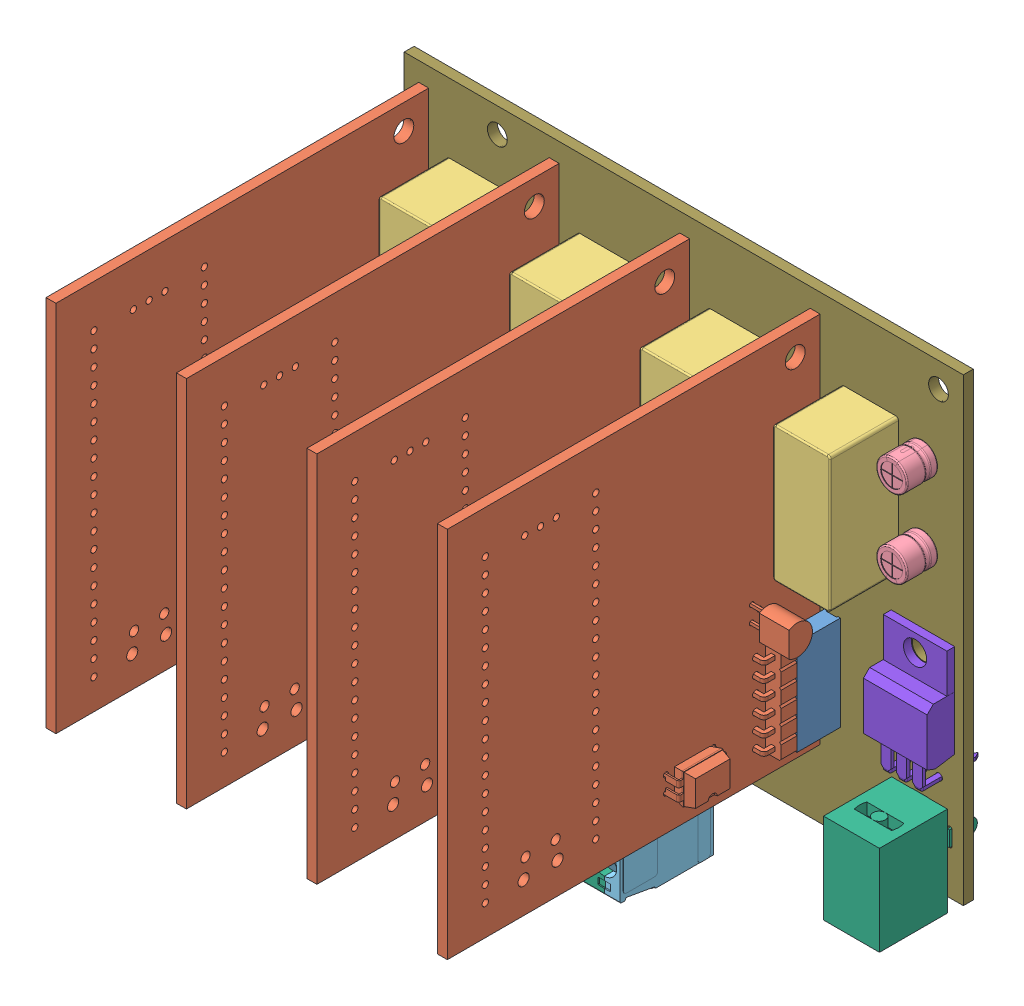
SolidWorks assembly scbs_array_pcba, configuration Default. Lengths in mm.
Overall size (91.35 87.17 67.03).
79 component instances, 27 part files, 3 mates.
Components (placement in the parent):
- PinSocket_1x06_P2.54mm_Vertical-1: PinSocket_1x06_P2.54mm_Vertical [PinSocket_1x06_P2.54mm_Vertical] at (47 -65 1.65) size (2.54 15.24 10.1)
  - SOLID-1: SOLID [SOLID] at origin size (2.54 15.24 10.1)
- scbs_pico-1: scbs_pico [scbs_pico] at (45.7 -102.3 87.35) x (0 0 -1) z (-1 0 0) size (60 60 13.4)
  - COMPOUND-1: COMPOUND [COMPOUND] at origin size (60 60 13.4)
- Converter_DCDC_TRACO_TMR-xxxx_THT-1: Converter_DCDC_TRACO_TMR-xxxx_THT [Converter_DCDC_TRACO_TMR-xxxx_THT] at (33 -33 1.65) x (0 -1 0) z (0 0 1) size (21.8 9.2 15)
  - SOLID-0-1: SOLID-0 [SOLID-0] at origin size (21.8 9.2 15)
- CP_Radial_D5.0mm_P2.50mm-1: CP_Radial_D5.0mm_P2.50mm [CP_Radial_D5.0mm_P2.50mm] at (61 -46 1.65) x (0 -1 0) z (0 0 1) size (6.13 6.52 7)
  - SOLID-1-1: SOLID-1 [SOLID-1] at origin size (6.13 6.52 7)
- CP_Radial_D5.0mm_P2.50mm-2: CP_Radial_D5.0mm_P2.50mm [CP_Radial_D5.0mm_P2.50mm] at (103.5 -46 1.65) x (0 -1 0) z (0 0 1) size (6.13 6.52 7)
  - SOLID-1-1: SOLID-1 [SOLID-1] at origin size (6.13 6.52 7)
- PinHeader_1x03_P2.54mm_Horizontal-1: PinHeader_1x03_P2.54mm_Horizontal [PinHeader_1x03_P2.54mm_Horizontal] at (36 -86 1.65) x (0 -1 0) z (0 0 1) size (10.36 7.62 5.54)
  - SOLID-2-1: SOLID-2 [SOLID-2] at origin size (10.36 7.62 5.54)
- CP_Radial_D5.0mm_P2.50mm-3: CP_Radial_D5.0mm_P2.50mm [CP_Radial_D5.0mm_P2.50mm] at (61 -36 1.65) x (0 1 0) z (0 0 1) size (6.13 6.52 7)
  - SOLID-1-1: SOLID-1 [SOLID-1] at origin size (6.13 6.52 7)
- CP_Radial_D5.0mm_P2.50mm-4: CP_Radial_D5.0mm_P2.50mm [CP_Radial_D5.0mm_P2.50mm] at (82 -46 1.65) x (0 -1 0) z (0 0 1) size (6.13 6.52 7)
  - SOLID-1-1: SOLID-1 [SOLID-1] at origin size (6.13 6.52 7)
- Converter_DCDC_TRACO_TMR-xxxx_THT-2: Converter_DCDC_TRACO_TMR-xxxx_THT [Converter_DCDC_TRACO_TMR-xxxx_THT] at (96.5 -33 1.65) x (0 -1 0) z (0 0 1) size (21.8 9.2 15)
  - SOLID-0-1: SOLID-0 [SOLID-0] at origin size (21.8 9.2 15)
- CP_Radial_D5.0mm_P2.50mm-5: CP_Radial_D5.0mm_P2.50mm [CP_Radial_D5.0mm_P2.50mm] at (40 -36 1.65) x (0 1 0) z (0 0 1) size (6.13 6.52 7)
  - SOLID-1-1: SOLID-1 [SOLID-1] at origin size (6.13 6.52 7)
- SOFNG_DC005-T20-1: SOFNG_DC005-T20 [SOFNG_DC005-T20] at (103 -89 1.65) x (0 -1 0) z (-1 0 0) size (14.5 15.45 9.3)
  - COMPOUND-3-1: COMPOUND-3 [COMPOUND-3] at origin size (14.5 15.45 9.3)
- PinSocket_1x06_P2.54mm_Vertical-2: PinSocket_1x06_P2.54mm_Vertical [PinSocket_1x06_P2.54mm_Vertical] at (68 -65 1.65) size (2.54 15.24 10.1)
  - SOLID-1: SOLID [SOLID] at origin size (2.54 15.24 10.1)
- scbs_pico-2: scbs_pico [scbs_pico] at (66.7 -102.3 87.35) x (0 0 -1) z (-1 0 0) size (60 60 13.4)
  - COMPOUND-1: COMPOUND [COMPOUND] at origin size (60 60 13.4)
- PhoenixContact_MSTBA_2,5_5-G-5,08_1x05_P5.08mm_Horizontal-1: PhoenixContact_MSTBA_2,5_5-G-5,08_1x05_P5.08mm_Horizontal [PhoenixContact_MSTBA_2,5_5-G-5,08_1x05_P5.08mm_Horizontal] at (47 -87 1.65) size (27.4 12 12.6)
  - SOLID-4-1: SOLID-4 [SOLID-4] at origin size (27.4 12 12.6)
- PinSocket_1x06_P2.54mm_Vertical-3: PinSocket_1x06_P2.54mm_Vertical [PinSocket_1x06_P2.54mm_Vertical] at (26 -65 1.65) size (2.54 15.24 10.1)
  - SOLID-1: SOLID [SOLID] at origin size (2.54 15.24 10.1)
- scbs_pico-3: scbs_pico [scbs_pico] at (24.7 -102.3 87.35) x (0 0 -1) z (-1 0 0) size (60 60 13.4)
  - COMPOUND-1: COMPOUND [COMPOUND] at origin size (60 60 13.4)
- Converter_DCDC_TRACO_TMR-xxxx_THT-3: Converter_DCDC_TRACO_TMR-xxxx_THT [Converter_DCDC_TRACO_TMR-xxxx_THT] at (54 -33 1.65) x (0 -1 0) z (0 0 1) size (21.8 9.2 15)
  - SOLID-0-1: SOLID-0 [SOLID-0] at origin size (21.8 9.2 15)
- CP_Radial_D5.0mm_P2.50mm-6: CP_Radial_D5.0mm_P2.50mm [CP_Radial_D5.0mm_P2.50mm] at (40 -46 1.65) x (0 -1 0) z (0 0 1) size (6.13 6.52 7)
  - SOLID-1-1: SOLID-1 [SOLID-1] at origin size (6.13 6.52 7)
- PinSocket_1x06_P2.54mm_Vertical-4: PinSocket_1x06_P2.54mm_Vertical [PinSocket_1x06_P2.54mm_Vertical] at (89 -65 1.65) size (2.54 15.24 10.1)
  - SOLID-1: SOLID [SOLID] at origin size (2.54 15.24 10.1)
- scbs_pico-4: scbs_pico [scbs_pico] at (87.7 -102.3 87.35) x (0 0 -1) z (-1 0 0) size (60 60 13.4)
  - COMPOUND-1: COMPOUND [COMPOUND] at origin size (60 60 13.4)
- TO-220-3_Horizontal_TabDown-1: TO-220-3_Horizontal_TabDown [TO-220-3_Horizontal_TabDown] at (101 -78 1.65) size (10.25 19.74 10.78)
  - SOLID-5-1: SOLID-5 [SOLID-5] at origin size (10.25 19.74 10.78)
- CP_Radial_D5.0mm_P2.50mm-7: CP_Radial_D5.0mm_P2.50mm [CP_Radial_D5.0mm_P2.50mm] at (82 -36 1.65) x (0 1 0) z (0 0 1) size (6.13 6.52 7)
  - SOLID-1-1: SOLID-1 [SOLID-1] at origin size (6.13 6.52 7)
- Converter_DCDC_TRACO_TMR-xxxx_THT-4: Converter_DCDC_TRACO_TMR-xxxx_THT [Converter_DCDC_TRACO_TMR-xxxx_THT] at (75 -33 1.65) x (0 -1 0) z (0 0 1) size (21.8 9.2 15)
  - SOLID-0-1: SOLID-0 [SOLID-0] at origin size (21.8 9.2 15)
- CP_Radial_D5.0mm_P2.50mm-8: CP_Radial_D5.0mm_P2.50mm [CP_Radial_D5.0mm_P2.50mm] at (103.5 -36 1.65) x (0 1 0) z (0 0 1) size (6.13 6.52 7)
  - SOLID-1-1: SOLID-1 [SOLID-1] at origin size (6.13 6.52 7)
- R_0805_2012Metric-1: R_0805_2012Metric [R_0805_2012Metric] at (98 -70 -0.05) x (-1 0 0) z (0 0 -1) size (2 1.2 0.45)
  - SOLID-6-1: SOLID-6 [SOLID-6] at origin size (2 1.2 0.45)
- C_0805_2012Metric-1: C_0805_2012Metric [C_0805_2012Metric] at (71 -50 -0.05) x (0 1 0) z (0 0 -1) size (2 1.25 1.25)
  - SOLID-7-1: SOLID-7 [SOLID-7] at origin size (2 1.25 1.25)
- D_MELF-1: D_MELF [D_MELF] at (103.54 -73.77 -0.05) x (-1 0 0) z (0 0 -1) size (5.8 2.2 2.2)
  - SOLID-8-1: SOLID-8 [SOLID-8] at origin size (5.8 2.2 2.2)
- C_0805_2012Metric-2: C_0805_2012Metric [C_0805_2012Metric] at (49.4 -50 -0.05) x (0 1 0) z (0 0 -1) size (2 1.25 1.25)
  - SOLID-7-1: SOLID-7 [SOLID-7] at origin size (2 1.25 1.25)
- R_0805_2012Metric-2: R_0805_2012Metric [R_0805_2012Metric] at (94 -70 -0.05) x (0 1 0) z (0 0 -1) size (2 1.2 0.45)
  - SOLID-6-1: SOLID-6 [SOLID-6] at origin size (2 1.2 0.45)
- C_0805_2012Metric-3: C_0805_2012Metric [C_0805_2012Metric] at (29 -50 -0.05) x (0 1 0) z (0 0 -1) size (2 1.25 1.25)
  - SOLID-7-1: SOLID-7 [SOLID-7] at origin size (2 1.25 1.25)
- C_0805_2012Metric-4: C_0805_2012Metric [C_0805_2012Metric] at (92.5 -50 -0.05) x (0 1 0) z (0 0 -1) size (2 1.25 1.25)
  - SOLID-7-1: SOLID-7 [SOLID-7] at origin size (2 1.25 1.25)
- scbs_array PCB-1: scbs_array PCB [scbs_array PCB] at origin size (90 74 1.6)
- pxc_1757048_06_MSTB-2-5-5-ST-5-08_3D-1: pxc_1757048_06_MSTB-2-5-5-ST-5-08_3D [pxc_1757048_06_MSTB-2-5-5-ST-5-08_3D] at (44.46 -106.94 1.705) size (25.46 18.3 15)
  - 2022_06_08_09_32_02_0871-1: 2022_06_08_09_32_02_0871 [2022_06_08_09_32_02_0871] at origin size (3.8 5 6.8)
  - 2022_06_08_09_32_02_0840-1: 2022_06_08_09_32_02_0840 [2022_06_08_09_32_02_0840] at origin size (3.82 3.82 6.8)
  - 2022_06_08_09_32_02_0809-1: 2022_06_08_09_32_02_0809 [2022_06_08_09_32_02_0809] at origin size (3.8 5 6.8)
  - 2022_06_08_09_32_02_0778-1: 2022_06_08_09_32_02_0778 [2022_06_08_09_32_02_0778] at origin size (3.82 3.82 6.8)
  - 2022_06_08_09_32_02_0746-1: 2022_06_08_09_32_02_0746 [2022_06_08_09_32_02_0746] at origin size (3.8 5 6.8)
  - 2022_06_08_09_32_02_0715-1: 2022_06_08_09_32_02_0715 [2022_06_08_09_32_02_0715] at origin size (3.82 3.82 6.8)
  - 2022_06_08_09_32_02_0684-1: 2022_06_08_09_32_02_0684 [2022_06_08_09_32_02_0684] at origin size (3.8 5 6.8)
  - 2022_06_08_09_32_02_0653-1: 2022_06_08_09_32_02_0653 [2022_06_08_09_32_02_0653] at origin size (3.82 3.82 6.8)
  - 2022_06_08_09_32_02_0635-1: 2022_06_08_09_32_02_0635 [2022_06_08_09_32_02_0635] at origin size (3.8 5 6.8)
  - 2022_06_08_09_32_02_0631-1: 2022_06_08_09_32_02_0631 [2022_06_08_09_32_02_0631] at origin size (3.82 3.82 6.8)
  - 2022_06_08_09_32_02_0627-1: 2022_06_08_09_32_02_0627 [2022_06_08_09_32_02_0627] at origin size (5.11 18.3 15)
  - 2022_06_08_09_32_02_0623-1: 2022_06_08_09_32_02_0623 [2022_06_08_09_32_02_0623] at origin size (5.08 18.3 15)
  - 2022_06_08_09_32_02_0619-1: 2022_06_08_09_32_02_0619 [2022_06_08_09_32_02_0619] at origin size (5.08 18.3 15)
  - 2022_06_08_09_32_02_0615-1: 2022_06_08_09_32_02_0615 [2022_06_08_09_32_02_0615] at origin size (5.08 18.3 15)
  - 2022_06_08_09_32_02_0611-1: 2022_06_08_09_32_02_0611 [2022_06_08_09_32_02_0611] at origin size (7.65 18.3 15)
Mates (geometry in assembly coordinates):
- Distance3: distance = 0.2 mm anti-aligned: plane of PhoenixContact_MSTBA_2,5_5-G-5,08_1x05_P5.08mm_Horizontal-1/SOLID-4-1 through (44.26 -97 8.55) normal (1 0 0); plane of pxc_1757048_06_MSTB-2-5-5-ST-5-08_3D-1/2022_06_08_09_32_02_0611-1 through (44.46 -88.4182 1.33) normal (-1 0 0)
- Distance2: distance = 0.2 mm anti-aligned: plane of PhoenixContact_MSTBA_2,5_5-G-5,08_1x05_P5.08mm_Horizontal-1/SOLID-4-1 through (70.06 -97 8.55) normal (0 0 -1); plane of pxc_1757048_06_MSTB-2-5-5-ST-5-08_3D-1/2022_06_08_09_32_02_0627-1 through (68.5429 -88.6617 8.35) normal (0 0 1)
- Distance1: distance = 0.2 mm anti-aligned: plane of PhoenixContact_MSTBA_2,5_5-G-5,08_1x05_P5.08mm_Horizontal-1/SOLID-4-1 through (43.46 -97 1.65) normal (0 -1 0); plane of pxc_1757048_06_MSTB-2-5-5-ST-5-08_3D-1/2022_06_08_09_32_02_0611-1 through (45.5487 -97.2 3.4479) normal (0 1 0)
